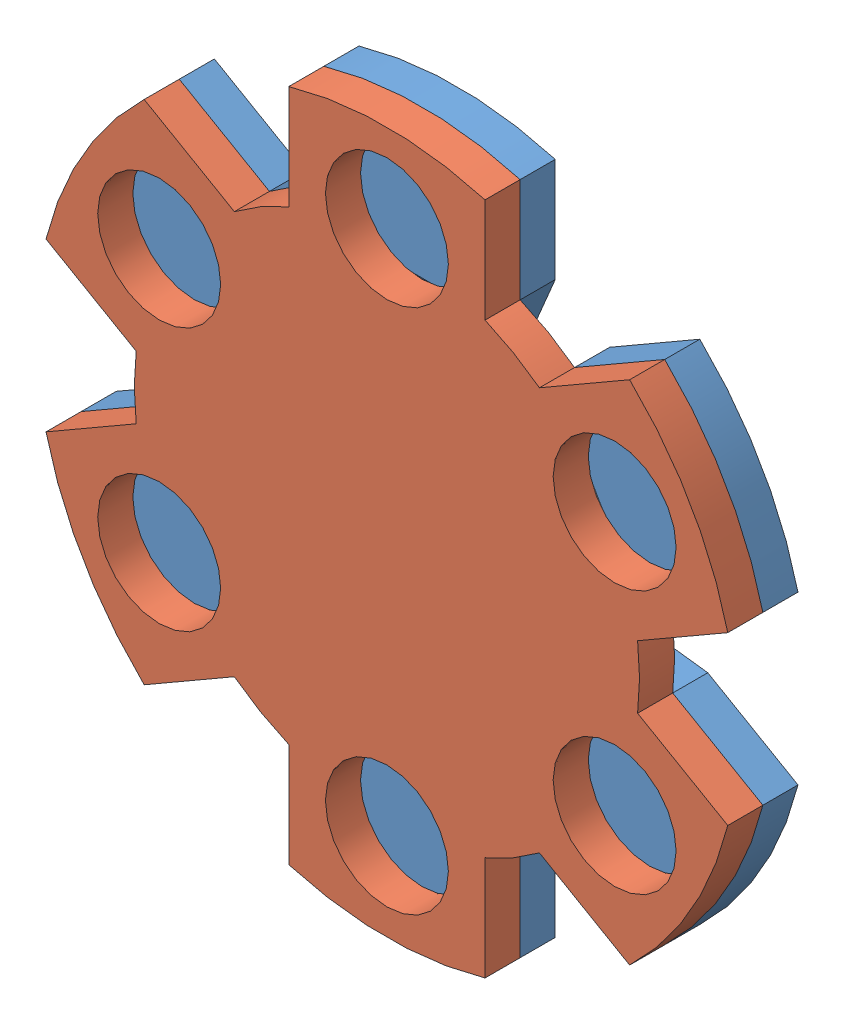
SolidWorks assembly fiducial_base_2, configuration Default. Lengths in mm.
Overall size (61.68 63.5 6.35).
2 component instances, 2 part files, 0 mates.
Components (placement in the parent):
- fiducial_mount_back_2-1: fiducial_mount_back_2 [Default] at (8.6967 17.7639 -18.2452) size (61.68 63.5 3.17)
- fiducial_mount_2-1: fiducial_mount_2 [Default] at (8.6967 17.7639 -15.0702) size (61.68 63.5 3.17)
